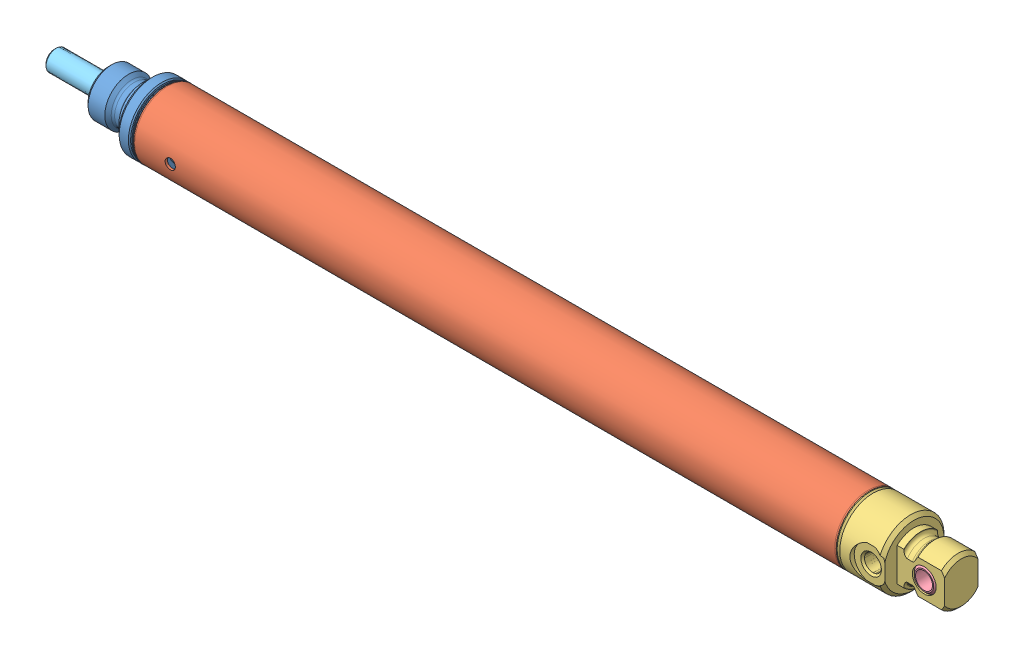
SolidWorks assembly 023_375-P, configuration Default. Lengths in mm.
Overall size (212.17 15.62 15.62).
6 component instances, 6 part files, 14 mates.
Components (placement in the parent):
- 023_375-P0000_0_dummy-1: 023_375-P0000_0_dummy [Default] at origin
- 02000-0_rod_guide-1: 02000-0_rod_guide [Default] at origin size (26.19 15.62 15.62)
- 02-6_4912-1: 02-6_4912 [Default] at (13.335 0 0) size (165.98 15.62 15.62)
- 02P0Y000_rear_head-1: 02P0Y000_rear_head [Default] at (174.8536 0 0) size (24.61 15.62 15.62)
- D-8597-1: D-8597 [Default] at (194.691 0 0) x (1 0 0) z (0 0 -1) size (5.55 5.55 7.92)
- 023_375-P0_rod-1: 023_375-P0_rod [Default] at origin size (187.55 14.44 14.44)
Mates (geometry in assembly coordinates):
- Distance2: distance = 0 mm aligned: plane of 02000-0_rod_guide-1 through (0 0 0) normal (1 0 0); plane of 023_375-P0000_0_dummy-1 through (0 0 0) normal (1 0 0)
- Coincident1: coincident aligned: line of 023_375-P0000_0_dummy-1 through (80.9 0 0) axis (-1 0 0); line of 02000-0_rod_guide-1 through (80.9 0 0) axis (-1 0 0)
- Angle3: planar angle = 0 rad aligned: plane of 02000-0_rod_guide-1 through (0 0 0) normal (0 0 -1); plane of 023_375-P0000_0_dummy-1 through (0 0 0) normal (0 0 -1)
- Distance4: distance = 0 mm aligned: plane of 02-6_4912-1 through (13.335 0 0) normal (1 0 0); plane of 02000-0_rod_guide-1 through (13.335 0 0) normal (1 0 0)
- Coincident2: coincident aligned: line of 02000-0_rod_guide-1 through (80.9 0 0) axis (-1 0 0); line of 02-6_4912-1 through (94.235 0 0) axis (-1 0 0)
- Angle6: planar angle = 0 rad aligned: plane of 02-6_4912-1 through (13.335 0 0) normal (0 0 -1); plane of 02000-0_rod_guide-1 through (0 0 0) normal (0 0 -1)
- Distance6: distance = 0 mm aligned: plane of 02P0Y000_rear_head-1 through (178.2064 0 0) normal (1 0 0); plane of 02-6_4912-1 through (178.2064 0 0) normal (1 0 0)
- Coincident3: coincident aligned: line of 02-6_4912-1 through (94.235 0 0) axis (-1 0 0); line of 02P0Y000_rear_head-1 through (255.7536 0 0) axis (-1 0 0)
- Angle9: planar angle = 0 rad aligned: plane of 02P0Y000_rear_head-1 through (174.8536 0 0) normal (0 0 -1); plane of 02-6_4912-1 through (13.335 0 0) normal (0 0 -1)
- Distance7: distance = 0 mm anti-aligned: plane of D-8597-1 through (194.691 0 0) normal (0 0 -1); plane of 02P0Y000_rear_head-1 through (174.8536 0 0) normal (0 0 1)
- Coincident4: coincident anti-aligned: line of 02P0Y000_rear_head-1 through (194.691 0 80.9) axis (0 0 -1); line of D-8597-1 through (194.691 0 -80.9) axis (0 0 1)
- Angle12: planar angle = 0 rad aligned: plane of D-8597-1; plane of 02P0Y000_rear_head-1 through (194.691 0 0) normal (1 0 0)
- LimitDistance2: limit distance = 0 mm aligned: plane of 023_375-P0_rod-1 through (0 0 0) normal (1 0 0); plane of 02000-0_rod_guide-1 through (0 0 0) normal (1 0 0)
- Coincident5: coincident aligned: line of 02000-0_rod_guide-1 through (80.9 0 0) axis (-1 0 0); line of 023_375-P0_rod-1 through (80.9 0 0) axis (-1 0 0)
